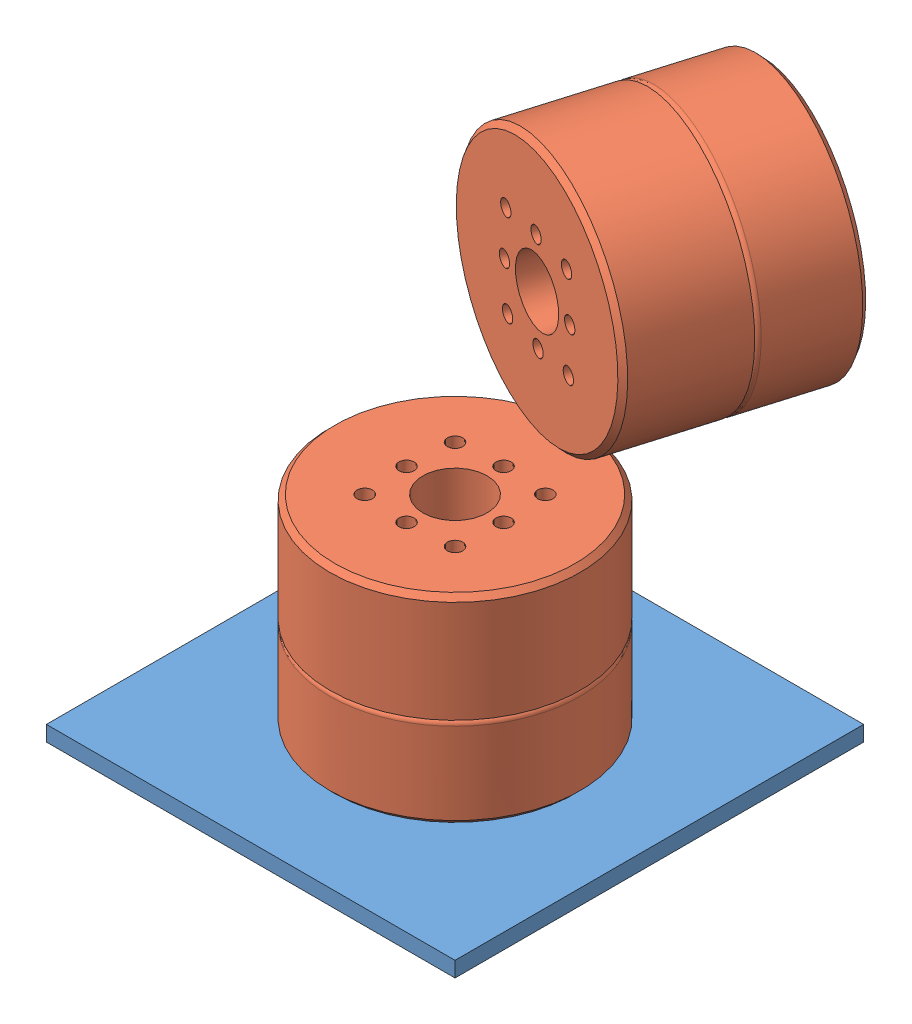
SolidWorks assembly 装配体2, configuration Default. Lengths in mm.
Overall size (85.07 116.07 116.07).
3 component instances, 2 part files, 5 mates.
Components (placement in the parent):
- 底座-1: 底座 [默认] at origin size (80 3 80)
- 无刷电机-1: 无刷电机 [默认] at (0 3 0) size (49 116.07 49)
- 无刷电机-2: 无刷电机 [默认] at (14.8129 72.0364 -49.7563) x (0.958004 0.029755 0.285208) z (0.028518 -0.999557 0.00849) size (49 116.07 49)
Mates (geometry in assembly coordinates):
- 同心1: concentric anti-aligned: circle of 底座-1; circle of 无刷电机-1
- 同心2: concentric anti-aligned: circle of 底座-1; circle of 无刷电机-1
- 重合3: coincident anti-aligned: plane of 底座-1 through (0 3 0) normal (0 1 0); plane of 无刷电机-1 through (0 3 0) normal (0 -1 0)
- 垂直1: perpendicular: plane of 底座-1 through (0 3 0) normal (0 1 0); plane of 无刷电机-2 through (14.8129 72.0364 -49.7563) normal (0.285334 0 -0.958428)
- 相切1: tangent aligned: cylinder of 无刷电机-1 through (0 42 0) axis (0 -1 0) radius 24.5; cylinder of 无刷电机-2 through (3.6849 72.0364 -12.3776) axis (0.285334 0 -0.958428) radius 24.5
